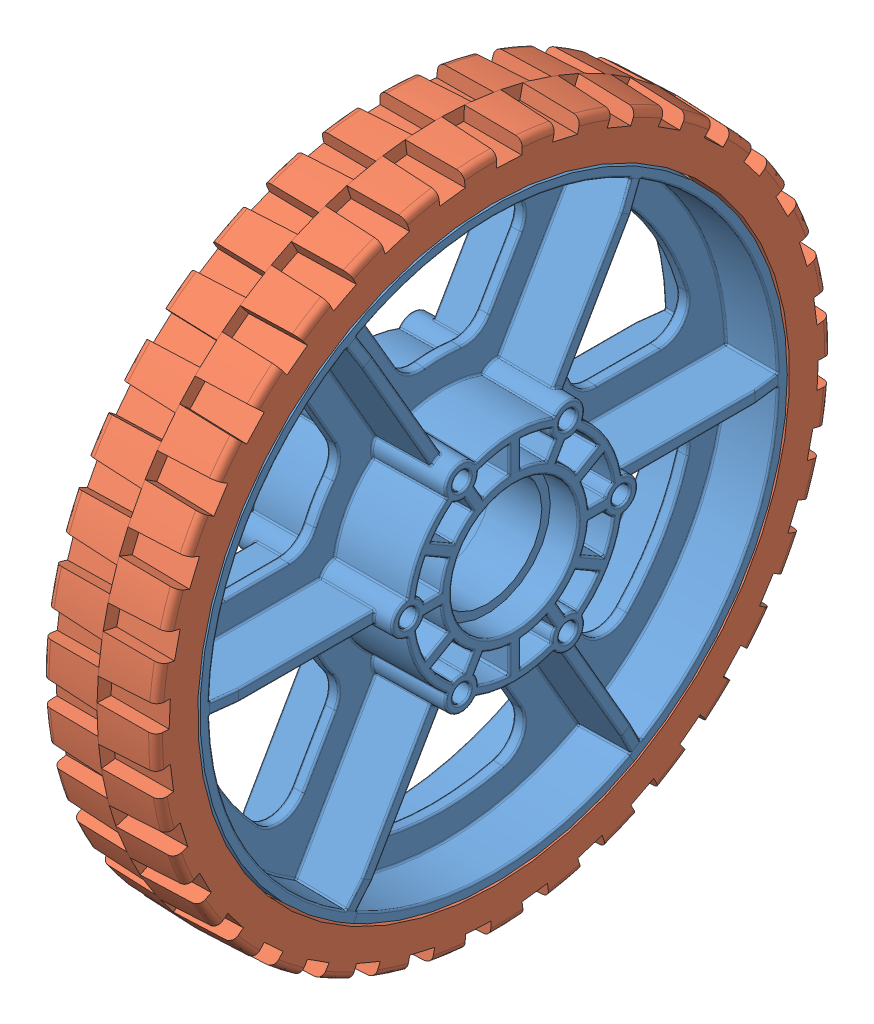
SolidWorks assembly Wheel_6inHiGrip, configuration Default. Lengths in mm.
Overall size (35.05 191.55 191.55).
2 component instances, 2 part files, 2 mates.
Components (placement in the parent):
- Wheel_6inHiGrip_Wheel-1: Wheel_6inHiGrip_Wheel [Default] at (-52.6446 9.4231 21.378) size (35.05 132.08 132.08)
- Wheel_6inHiGrip_Tread-1: Wheel_6inHiGrip_Tread [Default] at (-65.3446 9.4231 21.378) x (0 -0.304368 -0.952555) z (1 0 0) size (152.4 152.4 25.58)
Mates (geometry in assembly coordinates):
- Concentric1: concentric anti-aligned: circle of Wheel_6inHiGrip_Wheel-1; circle of Wheel_6inHiGrip_Tread-1
- Coincident1: coincident aligned: plane of Wheel_6inHiGrip_Wheel-1 through (-39.9446 9.4231 21.378) normal (1 0 0); plane of Wheel_6inHiGrip_Tread-1 through (-39.9446 29.6008 84.5266) normal (1 0 0)
